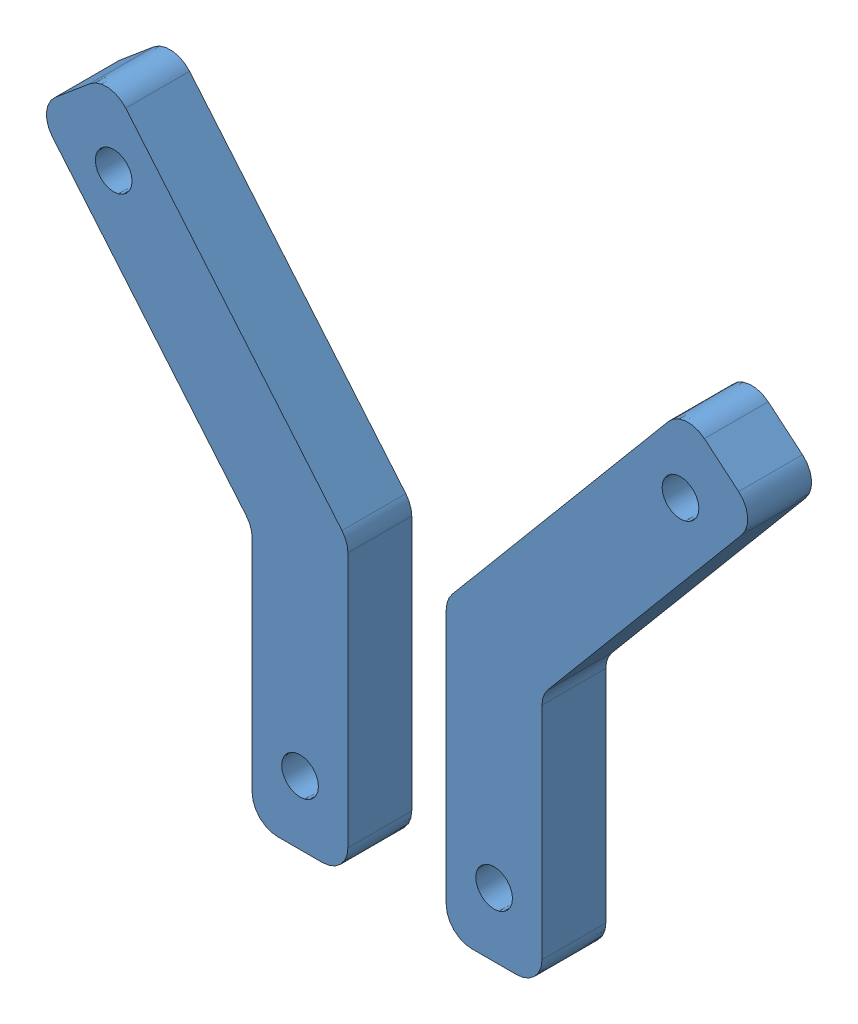
SolidWorks assembly hopper_assembly, configuration Default. Lengths in mm.
Overall size (69.76 56.11 6.35).
2 component instances, 1 part files, 3 mates.
Components (placement in the parent):
- hopper-1: hopper [Default] at (-72.4287 41.2853 19.2071) size (29.99 56.11 6.35)
- hopper-2: hopper [Default] at (-0.5917 41.2853 25.5571) x (-1 0 0) z (0 0 -1) size (29.99 56.11 6.35)
Mates (geometry in assembly coordinates):
- Distance1: distance = 9.779 mm: plane of assembly; plane of assembly; plane of hopper-1 through (-41.3997 19.1247 25.5571) normal (1 0 0); plane of hopper-2 through (-31.6207 19.1247 19.2071) normal (-1 0 0)
- Coincident2: coincident: plane of assembly; plane of assembly; plane of hopper-1 through (-72.4287 41.2853 25.5571) normal (0 0 1); plane of hopper-2 through (-0.5917 41.2853 25.5571) normal (0 0 1)
- Coincident4: coincident: plane of assembly; plane of assembly; plane of hopper-1 through (-50.9247 -9.7421 25.5571) normal (0 -1 0); plane of hopper-2 through (-22.0957 -9.7421 19.2071) normal (0 -1 0)
